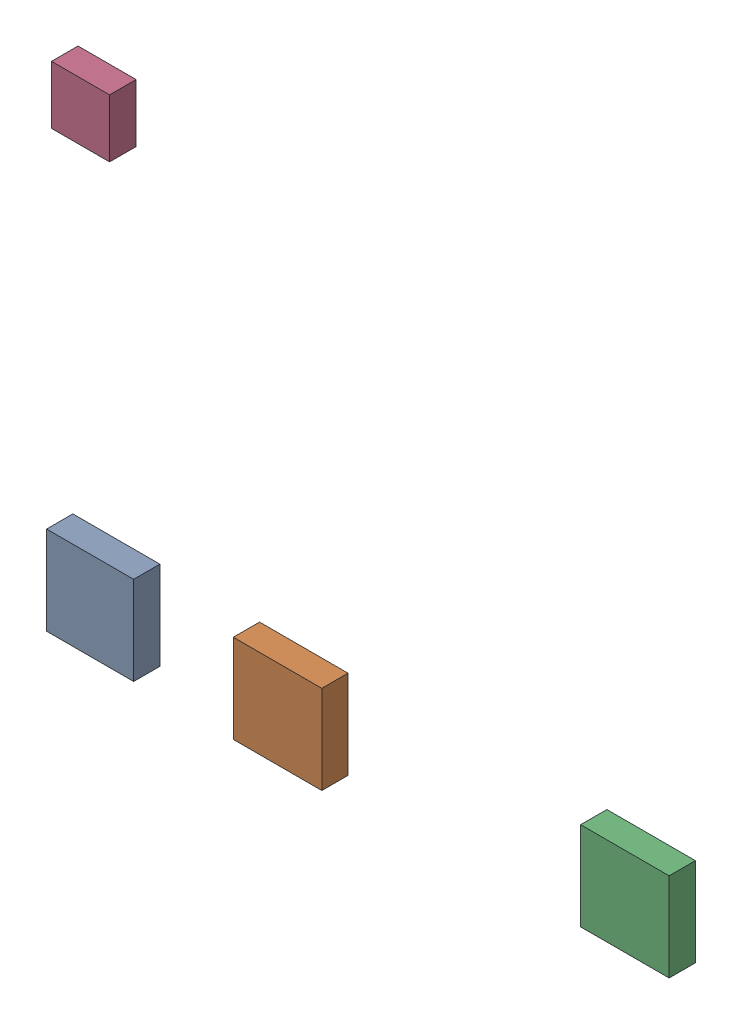
SolidWorks assembly Free-Models, configuration Default. Lengths in mm.
Overall size (107.18 85.46 4.57).
8 component instances, 3 part files, 0 mates.
Components (placement in the parent):
- 378152640-1: 378152640 [Default] at (46.355 67.31 0.05) size (14.99 15.24 4.52)
  - Extruded_26-1: Extruded_26 [Default] at origin size (14.99 15.24 4.52)
- 378152256-1: 378152256 [Default] at (78.625 67.25 0.05) size (15.24 15.24 4.52)
  - Extruded_27-1: Extruded_27 [Default] at origin size (15.24 15.24 4.52)
- 378152256-2: 378152256 [Default] at (138.425 69.2 0.05) size (15.24 15.24 4.52)
  - Extruded_27-1: Extruded_27 [Default] at origin size (15.24 15.24 4.52)
- 425993344-1: 425993344 [Default] at (44.704 140.088 0) size (10 10 4.57)
  - Extruded_28-1: Extruded_28 [Default] at origin size (10 10 4.57)
